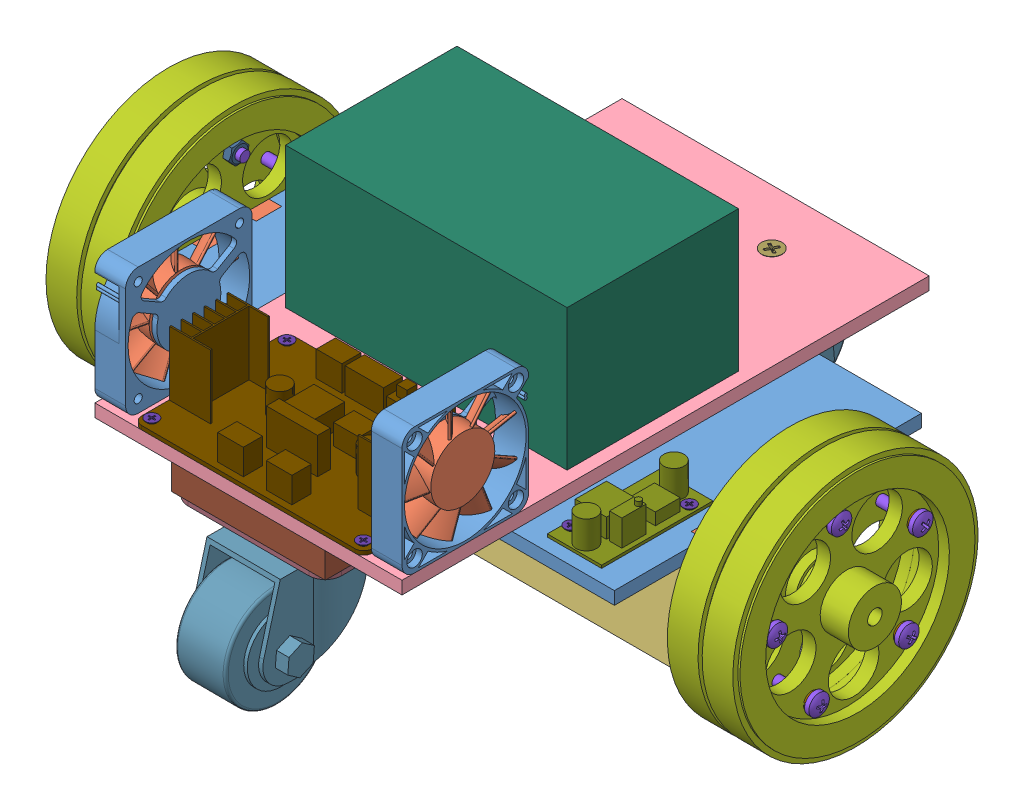
SolidWorks assembly MACM010000_BaseAssy, configuration 默认. Lengths in mm.
Overall size (283.6 149.04 243.22).
94 component instances, 20 part files, 55 mates.
Components (placement in the parent):
- MACM010100_Base-1: MACM010100_Base [默认] at (-8.5802 22.7565 6) size (200 55 206)
  - MACM010103_BasePlateC-1: MACM010103_BasePlateC [默认] at (5.4574 14.5542 200) size (200 5 120)
  - MACM010101_BasePlateA-1: MACM010101_BasePlateA [默认] at (-89.5426 -5.4458 200) x (0 0 1) z (0 -1 0) size (50 5 50)
  - MACM010101_BasePlateA-3: MACM010101_BasePlateA [默认] at (105.4574 -5.4458 200) x (0 0 1) z (0 -1 0) size (50 5 50)
  - MACM010102_BasePlateB-1: MACM010102_BasePlateB [默认] at (5.4574 -7.9458 225) x (-1 0 0) z (0 -1 0) size (200 5 45)
  - MACM010102_BasePlateB-3: MACM010102_BasePlateB [默认] at (5.4574 -7.9458 180) x (-1 0 0) z (0 -1 0) size (200 5 45)
  - MACM010104_BasePlateD-1: MACM010104_BasePlateD [默认] at (5.4574 19.5542 200) x (0 0 1) z (-1 0 0) size (206 5 120)
- MACM010001_Motor_75w-1: MACM010001_Motor_75w [默认] at (-98.1229 17.3107 206) size (106.7 37 37)
- MACM010001_Motor_75w-3: MACM010001_Motor_75w [默认] at (91.8771 17.3107 206) x (-1 0 0) z (0 0 -1) size (106.7 37 37)
- GB_CROSS_SCREWS_TYPE1 M3X12-12  H type-N-1: GB_CROSS_SCREWS_TYPE1 M3X12-12  H type-N [GB_CROSS_SCREWS_TYPE1 M3X12-12  H type-N] at (-105.5229 30.7341 198.25) size (14.39 5.6 5.6)
- GB_CROSS_SCREWS_TYPE1 M3X12-12  H type-N-2: GB_CROSS_SCREWS_TYPE1 M3X12-12  H type-N [GB_CROSS_SCREWS_TYPE1 M3X12-12  H type-N] at (-105.5229 17.3107 190.5) x (1 0 0) z (0 0.866025 0.5) size (14.39 5.6 5.6)
- GB_CROSS_SCREWS_TYPE1 M3X12-12  H type-N-3: GB_CROSS_SCREWS_TYPE1 M3X12-12  H type-N [GB_CROSS_SCREWS_TYPE1 M3X12-12  H type-N] at (-105.5229 3.8873 198.25) x (1 0 0) z (0 0.866025 -0.5) size (14.39 5.6 5.6)
- GB_CROSS_SCREWS_TYPE1 M3X12-12  H type-N-4: GB_CROSS_SCREWS_TYPE1 M3X12-12  H type-N [GB_CROSS_SCREWS_TYPE1 M3X12-12  H type-N] at (-105.5229 3.8873 213.75) x (1 0 0) z (0 0 -1) size (14.39 5.6 5.6)
- GB_CROSS_SCREWS_TYPE1 M3X12-12  H type-N-5: GB_CROSS_SCREWS_TYPE1 M3X12-12  H type-N [GB_CROSS_SCREWS_TYPE1 M3X12-12  H type-N] at (-105.5229 17.3107 221.5) x (1 0 0) z (0 -0.866025 -0.5) size (14.39 5.6 5.6)
- GB_CROSS_SCREWS_TYPE1 M3X12-12  H type-N-6: GB_CROSS_SCREWS_TYPE1 M3X12-12  H type-N [GB_CROSS_SCREWS_TYPE1 M3X12-12  H type-N] at (-105.5229 30.7341 213.75) x (1 0 0) z (0 -0.866025 0.5) size (14.39 5.6 5.6)
- GB_CROSS_SCREWS_TYPE1 M3X12-12  H type-N-8: GB_CROSS_SCREWS_TYPE1 M3X12-12  H type-N [GB_CROSS_SCREWS_TYPE1 M3X12-12  H type-N] at (99.2771 3.8873 213.75) x (-1 0 0) z (0 -0.924225 -0.381849) size (14.39 5.6 5.6)
- GB_CROSS_SCREWS_TYPE1 M3X12-12  H type-N-9: GB_CROSS_SCREWS_TYPE1 M3X12-12  H type-N [GB_CROSS_SCREWS_TYPE1 M3X12-12  H type-N] at (99.2771 3.8873 198.25) x (-1 0 0) z (0 -0.131421 -0.991327) size (14.39 5.6 5.6)
- GB_CROSS_SCREWS_TYPE1 M3X12-12  H type-N-10: GB_CROSS_SCREWS_TYPE1 M3X12-12  H type-N [GB_CROSS_SCREWS_TYPE1 M3X12-12  H type-N] at (99.2771 17.3107 190.5) x (-1 0 0) z (0 0.792804 -0.609477) size (14.39 5.6 5.6)
- GB_CROSS_SCREWS_TYPE1 M3X12-12  H type-N-11: GB_CROSS_SCREWS_TYPE1 M3X12-12  H type-N [GB_CROSS_SCREWS_TYPE1 M3X12-12  H type-N] at (99.2771 30.7341 198.25) x (-1 0 0) z (0 0.924225 0.381849) size (14.39 5.6 5.6)
- GB_CROSS_SCREWS_TYPE1 M3X12-12  H type-N-12: GB_CROSS_SCREWS_TYPE1 M3X12-12  H type-N [GB_CROSS_SCREWS_TYPE1 M3X12-12  H type-N] at (99.2771 30.7341 213.75) x (-1 0 0) z (0 0.131421 0.991327) size (14.39 5.6 5.6)
- GB_CROSS_SCREWS_TYPE1 M3X12-12  H type-N-13: GB_CROSS_SCREWS_TYPE1 M3X12-12  H type-N [GB_CROSS_SCREWS_TYPE1 M3X12-12  H type-N] at (99.2771 17.3107 221.5) x (-1 0 0) z (0 -0.792804 0.609477) size (14.39 5.6 5.6)
- MACM010300_DrivingWheel-1: MACM010300_DrivingWheel [默认] at (94.5266 112.8584 231.864) x (-1 0 0) z (0 -0.924225 -0.381849) size (40.8 108.78 108.78)
  - MACM010301_DrivingWheel-1: MACM010301_DrivingWheel [默认] at (-30.5506 -9.9077 91.7141) size (20.4 95.8 95.8)
  - MACM010301_DrivingWheel-2: MACM010301_DrivingWheel [默认] at (-16.9506 -9.9077 91.7141) x (-1 0 0) z (0 -0.989252 -0.146219) size (20.4 95.8 95.8)
  - GB_CROSS_SCREWS_TYPE1 M4X25-25  H type-N-1: GB_CROSS_SCREWS_TYPE1 M4X25-25  H type-N [GB_CROSS_SCREWS_TYPE1 M4X25-25  H type-N] at (-37.3506 -2.9981 62.2638) size (28.07 8 8)
  - GB_FASTENER_WASHER_SW 4-1: GB_FASTENER_WASHER_SW 4 [GB_FASTENER_WASHER_SW 4] at (-33.1506 -2.9981 62.2638) x (0 0 -1) z (1 0 0) size (6.6 6.6 1.1)
  - GB_FASTENER_NUT_SNAB1 M4-N-1: GB_FASTENER_NUT_SNAB1 M4-N [GB_FASTENER_NUT_SNAB1 M4-N] at (-14.3506 -2.9981 62.2638) x (0 0 1) z (-1 0 0) size (8.08 7 3.2)
  - GB_FASTENER_NUT_SNAB1 M4-N-2: GB_FASTENER_NUT_SNAB1 M4-N [GB_FASTENER_NUT_SNAB1 M4-N] at (-14.3506 -35.7814 76.042) x (0 0.951057 0.309017) z (-1 0 0) size (8.08 7 3.2)
  - GB_FASTENER_NUT_SNAB1 M4-N-3: GB_FASTENER_NUT_SNAB1 M4-N [GB_FASTENER_NUT_SNAB1 M4-N] at (-14.3506 -32.8082 111.4785) x (0 0.587785 -0.809017) z (-1 0 0) size (8.08 7 3.2)
  - GB_FASTENER_NUT_SNAB1 M4-N-4: GB_FASTENER_NUT_SNAB1 M4-N [GB_FASTENER_NUT_SNAB1 M4-N] at (-14.3506 1.8127 119.6012) x (0 -0.587785 -0.809017) z (-1 0 0) size (8.08 7 3.2)
  - GB_FASTENER_NUT_SNAB1 M4-N-5: GB_FASTENER_NUT_SNAB1 M4-N [GB_FASTENER_NUT_SNAB1 M4-N] at (-14.3506 20.2364 89.1849) x (0 -0.951057 0.309017) z (-1 0 0) size (8.08 7 3.2)
  - GB_FASTENER_WASHER_SW 4-2: GB_FASTENER_WASHER_SW 4 [GB_FASTENER_WASHER_SW 4] at (-33.1506 -35.7814 76.042) x (0 -0.951057 -0.309017) z (1 0 0) size (6.6 6.6 1.1)
  - GB_FASTENER_WASHER_SW 4-3: GB_FASTENER_WASHER_SW 4 [GB_FASTENER_WASHER_SW 4] at (-33.1506 -32.8082 111.4785) x (0 -0.587785 0.809017) z (1 0 0) size (6.6 6.6 1.1)
  - GB_FASTENER_WASHER_SW 4-4: GB_FASTENER_WASHER_SW 4 [GB_FASTENER_WASHER_SW 4] at (-33.1506 1.8127 119.6012) x (0 0.587785 0.809017) z (1 0 0) size (6.6 6.6 1.1)
  - GB_FASTENER_WASHER_SW 4-5: GB_FASTENER_WASHER_SW 4 [GB_FASTENER_WASHER_SW 4] at (-33.1506 20.2364 89.1849) x (0 0.951057 -0.309017) z (1 0 0) size (6.6 6.6 1.1)
  - GB_CROSS_SCREWS_TYPE1 M4X25-25  H type-N-2: GB_CROSS_SCREWS_TYPE1 M4X25-25  H type-N [GB_CROSS_SCREWS_TYPE1 M4X25-25  H type-N] at (-37.3506 -35.7814 76.042) x (1 0 0) z (0 0.951057 0.309017) size (28.07 8 8)
  - GB_CROSS_SCREWS_TYPE1 M4X25-25  H type-N-3: GB_CROSS_SCREWS_TYPE1 M4X25-25  H type-N [GB_CROSS_SCREWS_TYPE1 M4X25-25  H type-N] at (-37.3506 -32.8082 111.4785) x (1 0 0) z (0 0.587785 -0.809017) size (28.07 8 8)
  - GB_CROSS_SCREWS_TYPE1 M4X25-25  H type-N-4: GB_CROSS_SCREWS_TYPE1 M4X25-25  H type-N [GB_CROSS_SCREWS_TYPE1 M4X25-25  H type-N] at (-37.3506 1.8127 119.6012) x (1 0 0) z (0 -0.587785 -0.809017) size (28.07 8 8)
  - GB_CROSS_SCREWS_TYPE1 M4X25-25  H type-N-5: GB_CROSS_SCREWS_TYPE1 M4X25-25  H type-N [GB_CROSS_SCREWS_TYPE1 M4X25-25  H type-N] at (-37.3506 20.2364 89.1849) x (1 0 0) z (0 -0.951057 0.309017) size (28.07 8 8)
- MACM010300_DrivingWheel-3: MACM010300_DrivingWheel [默认] at (-100.7723 34.2184 114.2859) size (40.8 108.78 108.78)
  - MACM010301_DrivingWheel-1: MACM010301_DrivingWheel [默认] at (-30.5506 -9.9077 91.7141) size (20.4 95.8 95.8)
  - MACM010301_DrivingWheel-2: MACM010301_DrivingWheel [默认] at (-16.9506 -9.9077 91.7141) x (-1 0 0) z (0 -0.989252 -0.146219) size (20.4 95.8 95.8)
  - GB_CROSS_SCREWS_TYPE1 M4X25-25  H type-N-1: GB_CROSS_SCREWS_TYPE1 M4X25-25  H type-N [GB_CROSS_SCREWS_TYPE1 M4X25-25  H type-N] at (-37.3506 -2.9981 62.2638) size (28.07 8 8)
  - GB_FASTENER_WASHER_SW 4-1: GB_FASTENER_WASHER_SW 4 [GB_FASTENER_WASHER_SW 4] at (-33.1506 -2.9981 62.2638) x (0 0 -1) z (1 0 0) size (6.6 6.6 1.1)
  - GB_FASTENER_NUT_SNAB1 M4-N-1: GB_FASTENER_NUT_SNAB1 M4-N [GB_FASTENER_NUT_SNAB1 M4-N] at (-14.3506 -2.9981 62.2638) x (0 0 1) z (-1 0 0) size (8.08 7 3.2)
  - GB_FASTENER_NUT_SNAB1 M4-N-2: GB_FASTENER_NUT_SNAB1 M4-N [GB_FASTENER_NUT_SNAB1 M4-N] at (-14.3506 -35.7814 76.042) x (0 0.951057 0.309017) z (-1 0 0) size (8.08 7 3.2)
  - GB_FASTENER_NUT_SNAB1 M4-N-3: GB_FASTENER_NUT_SNAB1 M4-N [GB_FASTENER_NUT_SNAB1 M4-N] at (-14.3506 -32.8082 111.4785) x (0 0.587785 -0.809017) z (-1 0 0) size (8.08 7 3.2)
  - GB_FASTENER_NUT_SNAB1 M4-N-4: GB_FASTENER_NUT_SNAB1 M4-N [GB_FASTENER_NUT_SNAB1 M4-N] at (-14.3506 1.8127 119.6012) x (0 -0.587785 -0.809017) z (-1 0 0) size (8.08 7 3.2)
  - GB_FASTENER_NUT_SNAB1 M4-N-5: GB_FASTENER_NUT_SNAB1 M4-N [GB_FASTENER_NUT_SNAB1 M4-N] at (-14.3506 20.2364 89.1849) x (0 -0.951057 0.309017) z (-1 0 0) size (8.08 7 3.2)
  - GB_FASTENER_WASHER_SW 4-2: GB_FASTENER_WASHER_SW 4 [GB_FASTENER_WASHER_SW 4] at (-33.1506 -35.7814 76.042) x (0 -0.951057 -0.309017) z (1 0 0) size (6.6 6.6 1.1)
  - GB_FASTENER_WASHER_SW 4-3: GB_FASTENER_WASHER_SW 4 [GB_FASTENER_WASHER_SW 4] at (-33.1506 -32.8082 111.4785) x (0 -0.587785 0.809017) z (1 0 0) size (6.6 6.6 1.1)
  - GB_FASTENER_WASHER_SW 4-4: GB_FASTENER_WASHER_SW 4 [GB_FASTENER_WASHER_SW 4] at (-33.1506 1.8127 119.6012) x (0 0.587785 0.809017) z (1 0 0) size (6.6 6.6 1.1)
  - GB_FASTENER_WASHER_SW 4-5: GB_FASTENER_WASHER_SW 4 [GB_FASTENER_WASHER_SW 4] at (-33.1506 20.2364 89.1849) x (0 0.951057 -0.309017) z (1 0 0) size (6.6 6.6 1.1)
  - GB_CROSS_SCREWS_TYPE1 M4X25-25  H type-N-2: GB_CROSS_SCREWS_TYPE1 M4X25-25  H type-N [GB_CROSS_SCREWS_TYPE1 M4X25-25  H type-N] at (-37.3506 -35.7814 76.042) x (1 0 0) z (0 0.951057 0.309017) size (28.07 8 8)
  - GB_CROSS_SCREWS_TYPE1 M4X25-25  H type-N-3: GB_CROSS_SCREWS_TYPE1 M4X25-25  H type-N [GB_CROSS_SCREWS_TYPE1 M4X25-25  H type-N] at (-37.3506 -32.8082 111.4785) x (1 0 0) z (0 0.587785 -0.809017) size (28.07 8 8)
  - GB_CROSS_SCREWS_TYPE1 M4X25-25  H type-N-4: GB_CROSS_SCREWS_TYPE1 M4X25-25  H type-N [GB_CROSS_SCREWS_TYPE1 M4X25-25  H type-N] at (-37.3506 1.8127 119.6012) x (1 0 0) z (0 -0.587785 -0.809017) size (28.07 8 8)
  - GB_CROSS_SCREWS_TYPE1 M4X25-25  H type-N-5: GB_CROSS_SCREWS_TYPE1 M4X25-25  H type-N [GB_CROSS_SCREWS_TYPE1 M4X25-25  H type-N] at (-37.3506 20.2364 89.1849) x (1 0 0) z (0 -0.951057 0.309017) size (28.07 8 8)
- MACM010200_UniversalWheelAssy-1: MACM010200_UniversalWheelAssy [默认] at (-2.2458 42.1931 227.5) x (-1 0 0) z (0 0 1) size (60 63.2 61.61)
  - MACM010201_UniversalWheelBase-1: MACM010201_UniversalWheelBase [默认] at (0.8771 -0.1176 60) size (60 10 43)
  - GB_WOOD_SCREWS_TYPE135 4X12-N-1: GB_WOOD_SCREWS_TYPE135 4X12-N [GB_WOOD_SCREWS_TYPE135 4X12-N] at (-21.6229 12.5624 45) x (0 -1 0) z (0.116507 0 0.99319) size (12 8 8)
  - GB_WOOD_SCREWS_TYPE135 4X12-N-5: GB_WOOD_SCREWS_TYPE135 4X12-N [GB_WOOD_SCREWS_TYPE135 4X12-N] at (23.3771 12.5624 75) x (0 -1 0) z (0.108363 0 0.994111) size (12 8 8)
  - GB_WOOD_SCREWS_TYPE135 4X12-N-7: GB_WOOD_SCREWS_TYPE135 4X12-N [GB_WOOD_SCREWS_TYPE135 4X12-N] at (23.3771 12.5624 45) x (0 -1 0) z (0.108363 0 0.994111) size (12 8 8)
  - GB_WOOD_SCREWS_TYPE135 4X12-N-9: GB_WOOD_SCREWS_TYPE135 4X12-N [GB_WOOD_SCREWS_TYPE135 4X12-N] at (-21.6229 12.5624 75) x (0 -1 0) z (0.108363 0 0.994111) size (12 8 8)
  - MACM010210_UniversalWheel-1: MACM010210_UniversalWheel [默认] at (60.8771 11.5671 62.179) x (0 0 1) z (-1 0 0) size (61.61 53.2 60)
    - MACM010211_UniversalWheelA_1.5inch-1: MACM010211_UniversalWheelA_1.5inch [默认] at (-2.179 -1.6848 60) size (43 6.68 60)
    - MACM010212_UniversalWheelB_1.5inch-1: MACM010212_UniversalWheelB_1.5inch [默认] at (-2.179 -1.6848 60) x (-0.005663 0 -0.999984) z (0.999984 0 -0.005663) size (38.6 46.52 57.75)
- GB_WOOD_SCREWS_TYPE135 4X12-N-9: GB_WOOD_SCREWS_TYPE135 4X12-N [GB_WOOD_SCREWS_TYPE135 4X12-N] at (16.8771 47.4107 287.5) x (0 -1 0) z (-0.453005 0 0.891508) size (12 8 8)
- GB_WOOD_SCREWS_TYPE135 4X12-N-3: GB_WOOD_SCREWS_TYPE135 4X12-N [GB_WOOD_SCREWS_TYPE135 4X12-N] at (-23.1229 47.4107 287.5) x (0 -1 0) z (-0.453005 0 0.891508) size (12 8 8)
- MACM010200_UniversalWheelAssy-3: MACM010200_UniversalWheelAssy [默认] at (-3.9999 42.1931 184.5) x (1 0 0) z (0 0 -1) size (60 63.2 61.61)
  - MACM010201_UniversalWheelBase-1: MACM010201_UniversalWheelBase [默认] at (0.8771 -0.1176 60) size (60 10 43)
  - GB_WOOD_SCREWS_TYPE135 4X12-N-1: GB_WOOD_SCREWS_TYPE135 4X12-N [GB_WOOD_SCREWS_TYPE135 4X12-N] at (-21.6229 12.5624 45) x (0 -1 0) z (0.116507 0 0.99319) size (12 8 8)
  - GB_WOOD_SCREWS_TYPE135 4X12-N-5: GB_WOOD_SCREWS_TYPE135 4X12-N [GB_WOOD_SCREWS_TYPE135 4X12-N] at (23.3771 12.5624 75) x (0 -1 0) z (0.108363 0 0.994111) size (12 8 8)
  - GB_WOOD_SCREWS_TYPE135 4X12-N-7: GB_WOOD_SCREWS_TYPE135 4X12-N [GB_WOOD_SCREWS_TYPE135 4X12-N] at (23.3771 12.5624 45) x (0 -1 0) z (0.108363 0 0.994111) size (12 8 8)
  - GB_WOOD_SCREWS_TYPE135 4X12-N-9: GB_WOOD_SCREWS_TYPE135 4X12-N [GB_WOOD_SCREWS_TYPE135 4X12-N] at (-21.6229 12.5624 75) x (0 -1 0) z (0.108363 0 0.994111) size (12 8 8)
  - MACM010210_UniversalWheel-1: MACM010210_UniversalWheel [默认] at (60.8771 11.5671 62.179) x (0 0 1) z (-1 0 0) size (61.61 53.2 60)
    - MACM010211_UniversalWheelA_1.5inch-1: MACM010211_UniversalWheelA_1.5inch [默认] at (-2.179 -1.6848 60) size (43 6.68 60)
    - MACM010212_UniversalWheelB_1.5inch-1: MACM010212_UniversalWheelB_1.5inch [默认] at (-2.179 -1.6848 60) x (-0.005663 0 -0.999984) z (0.999984 0 -0.005663) size (38.6 46.52 57.75)
- GB_WOOD_SCREWS_TYPE135 4X12-N-11: GB_WOOD_SCREWS_TYPE135 4X12-N [GB_WOOD_SCREWS_TYPE135 4X12-N] at (16.8771 47.4107 124.5) x (0 -1 0) z (-0.453005 0 0.891508) size (12 8 8)
- GB_WOOD_SCREWS_TYPE135 4X12-N-13: GB_WOOD_SCREWS_TYPE135 4X12-N [GB_WOOD_SCREWS_TYPE135 4X12-N] at (-23.1229 47.4107 124.5) x (0 -1 0) z (-0.453005 0 0.891508) size (12 8 8)
- MACM010003_Battery-1: MACM010003_Battery [默认] at (-3.1229 74.8107 206) x (0 -1 0) z (1 0 0) size (55 67 110)
- MACM010004_Transformer_12v5v-1: MACM010004_Transformer_12v5v [默认] at (76.2771 42.3107 239.25) size (21.2 13 43.5)
- GB_WOOD_SCREWS_TYPE135 2.5X8-N-1: GB_WOOD_SCREWS_TYPE135 2.5X8-N [GB_WOOD_SCREWS_TYPE135 2.5X8-N] at (68.2771 44.4107 254.4) x (0 -1 0) z (0 0 1) size (8 5 5)
- GB_WOOD_SCREWS_TYPE135 2.5X8-N-3: GB_WOOD_SCREWS_TYPE135 2.5X8-N [GB_WOOD_SCREWS_TYPE135 2.5X8-N] at (84.2771 44.4107 224.1) x (0 -1 0) z (0 0 1) size (8 5 5)
- MACM010002_MotorDriver-1: MACM010002_MotorDriver [默认] at (-3.1229 47.3107 279) x (-1 0 0) z (0 0 -1) size (90 26.5 60)
- GB_WOOD_SCREWS_TYPE135 2.5X8-N-5: GB_WOOD_SCREWS_TYPE135 2.5X8-N [GB_WOOD_SCREWS_TYPE135 2.5X8-N] at (-44.4729 49.8107 305.4) x (0 -1 0) z (0 0 1) size (8 5 5)
- GB_WOOD_SCREWS_TYPE135 2.5X8-N-7: GB_WOOD_SCREWS_TYPE135 2.5X8-N [GB_WOOD_SCREWS_TYPE135 2.5X8-N] at (38.2271 49.8107 305.4) x (0 -1 0) z (0 0 1) size (8 5 5)
- GB_WOOD_SCREWS_TYPE135 2.5X8-N-9: GB_WOOD_SCREWS_TYPE135 2.5X8-N [GB_WOOD_SCREWS_TYPE135 2.5X8-N] at (-44.4729 49.8107 252.6) x (0 -1 0) z (0 0 1) size (8 5 5)
- GB_WOOD_SCREWS_TYPE135 2.5X8-N-11: GB_WOOD_SCREWS_TYPE135 2.5X8-N [GB_WOOD_SCREWS_TYPE135 2.5X8-N] at (38.2271 49.8107 252.6) x (0 -1 0) z (0 0 1) size (8 5 5)
- MACM010500_Fan_50X50X12-1: MACM010500_Fan_50X50X12 [默认] at (50.4938 71.5842 234.75) x (0 -1 0) z (0 0 1) size (52.76 12.48 52.76)
  - MACM010501_FanShell_50X50X12-1: MACM010501_FanShell_50X50X12 [默认] at (-0.4765 -5.5967 49.5) size (49.5 12.48 49.5)
  - MACM010502_Fanblade_50X50X12-1: MACM010502_Fanblade_50X50X12 [默认] at (-0.4765 1.4033 49.5) x (-0.987133 0 -0.1599) z (-0.1599 0 0.987133) size (46 8.03 46)
- MACM010500_Fan_50X50X12-3: MACM010500_Fan_50X50X12 [默认] at (-56.7396 71.5842 333.75) x (0 -1 0) z (0 0 -1) size (52.76 12.48 52.76)
  - MACM010501_FanShell_50X50X12-1: MACM010501_FanShell_50X50X12 [默认] at (-0.4765 -5.5967 49.5) size (49.5 12.48 49.5)
  - MACM010502_Fanblade_50X50X12-1: MACM010502_Fanblade_50X50X12 [默认] at (-0.4765 1.4033 49.5) x (-0.987133 0 -0.1599) z (-0.1599 0 0.987133) size (46 8.03 46)
Mates (geometry in assembly coordinates):
- 同心1: concentric anti-aligned: cylinder of MACM010100_Base-1/MACM010101_BasePlateA-1 through (-103.1229 17.3107 190.5) axis (1 0 0) radius 1.7; cylinder of MACM010001_Motor_75w-1 through (-86.1229 17.3107 190.5) axis (-1 0 0) radius 1.5
- 同心2: concentric anti-aligned: cylinder of MACM010100_Base-1/MACM010101_BasePlateA-1 through (-103.1229 17.3107 221.5) axis (1 0 0) radius 1.7; cylinder of MACM010001_Motor_75w-1 through (-86.1229 17.3107 221.5) axis (-1 0 0) radius 1.5
- 重合1: coincident anti-aligned: plane of MACM010100_Base-1/MACM010101_BasePlateA-1 through (-98.1229 17.3107 206) normal (1 0 0); plane of MACM010001_Motor_75w-1 through (-98.1229 17.3107 206) normal (-1 0 0)
- 同心3: concentric aligned: cylinder of MACM010001_Motor_75w-3 through (79.8771 17.3107 221.5) axis (1 0 0) radius 1.5; cylinder of MACM010100_Base-1/MACM010101_BasePlateA-3 through (91.8771 17.3107 221.5) axis (1 0 0) radius 1.7
- 同心4: concentric aligned: cylinder of MACM010100_Base-1/MACM010101_BasePlateA-3 through (91.8771 17.3107 190.5) axis (1 0 0) radius 1.7; cylinder of MACM010001_Motor_75w-3 through (79.8771 17.3107 190.5) axis (1 0 0) radius 1.5
- 重合2: coincident anti-aligned: plane of MACM010100_Base-1/MACM010101_BasePlateA-3 through (91.8771 17.3107 206) normal (-1 0 0); plane of MACM010001_Motor_75w-3 through (91.8771 17.3107 206) normal (1 0 0)
- 重合3: coincident anti-aligned: plane of MACM010100_Base-1/MACM010101_BasePlateA-1 through (-103.1229 17.3107 206) normal (-1 0 0); plane of GB_CROSS_SCREWS_TYPE1 M3X12-12  H type-N-1 through (-103.1229 32.5341 198.25) normal (1 0 0)
- 同心6: concentric aligned: cylinder of MACM010100_Base-1/MACM010101_BasePlateA-1 through (-103.1229 30.7341 198.25) axis (1 0 0) radius 1.7; cylinder of GB_CROSS_SCREWS_TYPE1 M3X12-12  H type-N-1 through (-101.0071 30.7341 198.25) axis (1 0 0) radius 1.5
- 重合4: coincident anti-aligned: plane of MACM010100_Base-1/MACM010101_BasePlateA-3 through (96.8771 17.3107 206) normal (1 0 0); plane of GB_CROSS_SCREWS_TYPE1 M3X12-12  H type-N-8 through (96.8771 4.5746 212.0864) normal (-1 0 0)
- 同心7: concentric anti-aligned: cylinder of MACM010100_Base-1/MACM010101_BasePlateA-3 through (91.8771 3.8873 213.75) axis (1 0 0) radius 1.7; cylinder of GB_CROSS_SCREWS_TYPE1 M3X12-12  H type-N-8 through (94.7613 3.8873 213.75) axis (-1 0 0) radius 1.5
- 重合5: coincident anti-aligned: plane of MACM010001_Motor_75w-3 through (97.8771 24.3107 206) normal (1 0 0); plane of MACM010300_DrivingWheel-1/MACM010301_DrivingWheel-2 through (97.8771 24.3107 206) normal (-1 0 0)
- 同心8: concentric anti-aligned: cylinder of MACM010001_Motor_75w-3 through (109.8771 24.3107 206) axis (-1 0 0) radius 3; cylinder of MACM010300_DrivingWheel-1/MACM010301_DrivingWheel-2 through (104.6771 24.3107 206) axis (1 0 0) radius 2.85
- 重合6: coincident anti-aligned: plane of MACM010001_Motor_75w-1 through (-104.1229 24.3107 206) normal (-1 0 0); plane of MACM010300_DrivingWheel-3/MACM010301_DrivingWheel-2 through (-104.1229 24.3107 206) normal (1 0 0)
- 同心9: concentric aligned: cylinder of MACM010001_Motor_75w-1 through (-116.1229 24.3107 206) axis (1 0 0) radius 3; cylinder of MACM010300_DrivingWheel-3/MACM010301_DrivingWheel-1 through (-138.1229 24.3107 206) axis (1 0 0) radius 2.85
- 重合7: coincident anti-aligned: plane of MACM010100_Base-1/MACM010104_BasePlateD-1 through (-3.1229 42.3107 206) normal (0 -1 0); plane of MACM010200_UniversalWheelAssy-1/MACM010201_UniversalWheelBase-1 through (-3.1229 42.3107 287.5) normal (0 1 0)
- 同心10: concentric anti-aligned: cylinder of MACM010100_Base-1/MACM010104_BasePlateD-1 through (-23.1229 42.3107 287.5) axis (0 1 0) radius 2.1; cylinder of MACM010200_UniversalWheelAssy-1/MACM010201_UniversalWheelBase-1 through (-23.1229 42.3107 287.5) axis (0 -1 0) radius 1.75
- 同心11: concentric anti-aligned: cylinder of MACM010100_Base-1/MACM010104_BasePlateD-1 through (16.8771 42.3107 287.5) axis (0 1 0) radius 2.1; cylinder of MACM010200_UniversalWheelAssy-1/MACM010201_UniversalWheelBase-1 through (16.8771 42.3107 287.5) axis (0 -1 0) radius 1.75
- 同心12: concentric aligned: cylinder of MACM010100_Base-1/MACM010104_BasePlateD-1 through (16.8771 42.3107 287.5) axis (0 1 0) radius 2.1; cylinder of GB_WOOD_SCREWS_TYPE135 4X12-N-9 through (16.8771 53.9172 287.5) axis (0 1 0) radius 2
- 距离1: distance = 0.1 mm aligned: plane of MACM010100_Base-1/MACM010104_BasePlateD-1 through (-3.1229 47.3107 206) normal (0 1 0); plane of GB_WOOD_SCREWS_TYPE135 4X12-N-9 through (18.6892 47.4107 283.934) normal (0 1 0)
- 同心13: concentric aligned: cylinder of MACM010100_Base-1/MACM010104_BasePlateD-1 through (-23.1229 42.3107 287.5) axis (0 1 0) radius 2.1; cylinder of GB_WOOD_SCREWS_TYPE135 4X12-N-3 through (-23.1229 53.9172 287.5) axis (0 1 0) radius 2
- 重合9: coincident aligned: plane of GB_WOOD_SCREWS_TYPE135 4X12-N-9 through (18.6892 47.4107 283.934) normal (0 1 0); plane of GB_WOOD_SCREWS_TYPE135 4X12-N-3 through (-21.3108 47.4107 283.934) normal (0 1 0)
- 同心14: concentric anti-aligned: cylinder of MACM010100_Base-1/MACM010104_BasePlateD-1 through (-23.1229 42.3107 124.5) axis (0 1 0) radius 2.1; cylinder of MACM010200_UniversalWheelAssy-3/MACM010201_UniversalWheelBase-1 through (-23.1229 42.3107 124.5) axis (0 -1 0) radius 1.75
- 同心15: concentric anti-aligned: cylinder of MACM010100_Base-1/MACM010104_BasePlateD-1 through (16.8771 42.3107 124.5) axis (0 1 0) radius 2.1; cylinder of MACM010200_UniversalWheelAssy-3/MACM010201_UniversalWheelBase-1 through (16.8771 42.3107 124.5) axis (0 -1 0) radius 1.75
- 重合10: coincident anti-aligned: plane of MACM010100_Base-1/MACM010104_BasePlateD-1 through (-3.1229 42.3107 206) normal (0 -1 0); plane of MACM010200_UniversalWheelAssy-3/MACM010201_UniversalWheelBase-1 through (-3.1229 42.3107 124.5) normal (0 1 0)
- 重合11: coincident aligned: plane of GB_WOOD_SCREWS_TYPE135 4X12-N-3 through (-21.3108 47.4107 283.934) normal (0 1 0); plane of GB_WOOD_SCREWS_TYPE135 4X12-N-11 through (18.6892 47.4107 120.934) normal (0 1 0)
- 重合12: coincident aligned: plane of GB_WOOD_SCREWS_TYPE135 4X12-N-11 through (18.6892 47.4107 120.934) normal (0 1 0); plane of GB_WOOD_SCREWS_TYPE135 4X12-N-13 through (-21.3108 47.4107 120.934) normal (0 1 0)
- 同心16: concentric aligned: cylinder of MACM010100_Base-1/MACM010104_BasePlateD-1 through (-23.1229 42.3107 124.5) axis (0 1 0) radius 2.1; cylinder of GB_WOOD_SCREWS_TYPE135 4X12-N-13 through (-23.1229 53.9172 124.5) axis (0 1 0) radius 2
- 同心17: concentric aligned: cylinder of MACM010100_Base-1/MACM010104_BasePlateD-1 through (16.8771 42.3107 124.5) axis (0 1 0) radius 2.1; cylinder of GB_WOOD_SCREWS_TYPE135 4X12-N-11 through (16.8771 53.9172 124.5) axis (0 1 0) radius 2
- 重合13: coincident anti-aligned: plane of MACM010100_Base-1/MACM010104_BasePlateD-1 through (-3.1229 47.3107 206) normal (0 1 0); plane of MACM010003_Battery-1 through (51.8771 47.3107 172.5) normal (0 -1 0)
- 重合14: coincident anti-aligned: plane of MACM010100_Base-1/MACM010104_BasePlateD-1 through (-3.1229 42.3107 206) normal (-1 0 0); plane of MACM010003_Battery-1 through (-3.1229 74.8107 206) normal (1 0 0)
- 重合17: coincident anti-aligned: plane of MACM010100_Base-1/MACM010103_BasePlateC-1 through (-3.1229 42.3107 206) normal (0 1 0); plane of MACM010004_Transformer_12v5v-1 through (76.2771 42.3107 239.25) normal (0 -1 0)
- 距离3: distance = 10 mm aligned: plane of MACM010100_Base-1/MACM010103_BasePlateC-1 through (96.8771 42.3107 266) normal (1 0 0); plane of MACM010004_Transformer_12v5v-1 through (86.8771 43.4107 261) normal (1 0 0)
- 距离4: distance = 5 mm aligned: plane of MACM010100_Base-1/MACM010103_BasePlateC-1 through (-103.1229 42.3107 266) normal (0 0 1); plane of MACM010004_Transformer_12v5v-1 through (86.8771 43.4107 261) normal (0 0 1)
- 重合20: coincident anti-aligned: plane of MACM010100_Base-1/MACM010104_BasePlateD-1 through (-3.1229 42.3107 206) normal (0 0 1); plane of MACM010003_Battery-1
- 同心18: concentric anti-aligned: cylinder of MACM010004_Transformer_12v5v-1 through (68.2771 43.4107 254.4) axis (0 -1 0) radius 1.4; cylinder of GB_WOOD_SCREWS_TYPE135 2.5X8-N-1 through (68.2771 50.9172 254.4) axis (0 1 0) radius 1.25
- 距离5: distance = 1 mm aligned: plane of MACM010004_Transformer_12v5v-1 through (76.2771 43.4107 239.25) normal (0 1 0); plane of GB_WOOD_SCREWS_TYPE135 2.5X8-N-1 through (68.2771 44.4107 251.9) normal (0 1 0)
- 同心19: concentric anti-aligned: cylinder of MACM010004_Transformer_12v5v-1 through (84.2771 43.4107 224.1) axis (0 -1 0) radius 1.4; cylinder of GB_WOOD_SCREWS_TYPE135 2.5X8-N-3 through (84.2771 50.9172 224.1) axis (0 1 0) radius 1.25
- 重合22: coincident aligned: plane of GB_WOOD_SCREWS_TYPE135 2.5X8-N-1 through (68.2771 44.4107 251.9) normal (0 1 0); plane of GB_WOOD_SCREWS_TYPE135 2.5X8-N-3 through (84.2771 44.4107 221.6) normal (0 1 0)
- 重合23: coincident anti-aligned: plane of MACM010100_Base-1/MACM010104_BasePlateD-1 through (-3.1229 47.3107 206) normal (0 1 0); plane of MACM010002_MotorDriver-1 through (38.5771 47.3107 252.3) normal (0 -1 0)
- 重合24: coincident aligned: plane of MACM010100_Base-1/MACM010104_BasePlateD-1 through (-63.1229 47.3107 309) normal (0 0 1); plane of MACM010002_MotorDriver-1 through (38.5771 48.8107 309) normal (0 0 1)
- 重合25: coincident anti-aligned: plane of MACM010003_Battery-1 through (-3.1229 74.8107 206) normal (1 0 0); plane of MACM010002_MotorDriver-1 through (-3.1229 47.3107 279) normal (-1 0 0)
- 重合26: coincident aligned: plane of GB_WOOD_SCREWS_TYPE135 2.5X8-N-5 through (-44.4729 49.8107 302.9) normal (0 1 0); plane of GB_WOOD_SCREWS_TYPE135 2.5X8-N-7 through (38.2271 49.8107 302.9) normal (0 1 0)
- 重合27: coincident aligned: plane of GB_WOOD_SCREWS_TYPE135 2.5X8-N-7 through (38.2271 49.8107 302.9) normal (0 1 0); plane of GB_WOOD_SCREWS_TYPE135 2.5X8-N-9 through (-44.4729 49.8107 250.1) normal (0 1 0)
- 重合28: coincident aligned: plane of GB_WOOD_SCREWS_TYPE135 2.5X8-N-9 through (-44.4729 49.8107 250.1) normal (0 1 0); plane of GB_WOOD_SCREWS_TYPE135 2.5X8-N-11 through (38.2271 49.8107 250.1) normal (0 1 0)
- 同心20: concentric anti-aligned: cylinder of MACM010002_MotorDriver-1 through (-44.4729 48.8107 305.4) axis (0 -1 0) radius 1.5; cylinder of GB_WOOD_SCREWS_TYPE135 2.5X8-N-5 through (-44.4729 56.3172 305.4) axis (0 1 0) radius 1.25
- 距离6: distance = 1 mm aligned: plane of GB_WOOD_SCREWS_TYPE135 2.5X8-N-5 through (-44.4729 49.8107 302.9) normal (0 1 0); plane of MACM010002_MotorDriver-1 through (38.5771 48.8107 252.3) normal (0 1 0)
- 同心21: concentric anti-aligned: cylinder of MACM010002_MotorDriver-1 through (38.2271 48.8107 305.4) axis (0 -1 0) radius 1.5; cylinder of GB_WOOD_SCREWS_TYPE135 2.5X8-N-7 through (38.2271 56.3172 305.4) axis (0 1 0) radius 1.25
- 同心22: concentric anti-aligned: cylinder of MACM010002_MotorDriver-1 through (-44.4729 48.8107 252.6) axis (0 -1 0) radius 1.5; cylinder of GB_WOOD_SCREWS_TYPE135 2.5X8-N-9 through (-44.4729 56.3172 252.6) axis (0 1 0) radius 1.25
- 同心23: concentric anti-aligned: cylinder of MACM010002_MotorDriver-1 through (38.2271 48.8107 252.6) axis (0 -1 0) radius 1.5; cylinder of GB_WOOD_SCREWS_TYPE135 2.5X8-N-11 through (38.2271 56.3172 252.6) axis (0 1 0) radius 1.25
- 重合30: coincident anti-aligned: plane of MACM010100_Base-1/MACM010104_BasePlateD-1 through (-3.1229 47.3107 206) normal (0 1 0); plane of MACM010500_Fan_50X50X12-1/MACM010501_FanShell_50X50X12-1 through (-51.1429 47.3107 309) normal (0 -1 0)
- 重合31: coincident aligned: plane of MACM010100_Base-1/MACM010104_BasePlateD-1 through (-63.1229 47.3107 309) normal (0 0 1); plane of MACM010500_Fan_50X50X12-1/MACM010501_FanShell_50X50X12-1 through (-51.1429 96.8107 309) normal (0 0 1)
- 重合32: coincident aligned: plane of MACM010500_Fan_50X50X12-1/MACM010501_FanShell_50X50X12-1 through (56.8771 72.0607 284.25) normal (1 0 0); plane of MACM010100_Base-1/MACM010104_BasePlateD-1 through (56.8771 47.3107 103) normal (1 0 0)
- 重合34: coincident anti-aligned: plane of MACM010100_Base-1/MACM010104_BasePlateD-1 through (-3.1229 47.3107 206) normal (0 1 0); plane of MACM010500_Fan_50X50X12-3/MACM010501_FanShell_50X50X12-1 through (44.8971 47.3107 259.5) normal (0 -1 0)
- 重合35: coincident aligned: plane of MACM010100_Base-1/MACM010104_BasePlateD-1 through (-63.1229 47.3107 103) normal (-1 0 0); plane of MACM010500_Fan_50X50X12-3/MACM010501_FanShell_50X50X12-1 through (-63.1229 72.0607 284.25) normal (-1 0 0)
- 重合36: coincident aligned: plane of MACM010100_Base-1/MACM010104_BasePlateD-1 through (-63.1229 47.3107 309) normal (0 0 1); plane of MACM010500_Fan_50X50X12-3/MACM010501_FanShell_50X50X12-1 through (44.8971 96.8107 309) normal (0 0 1)
